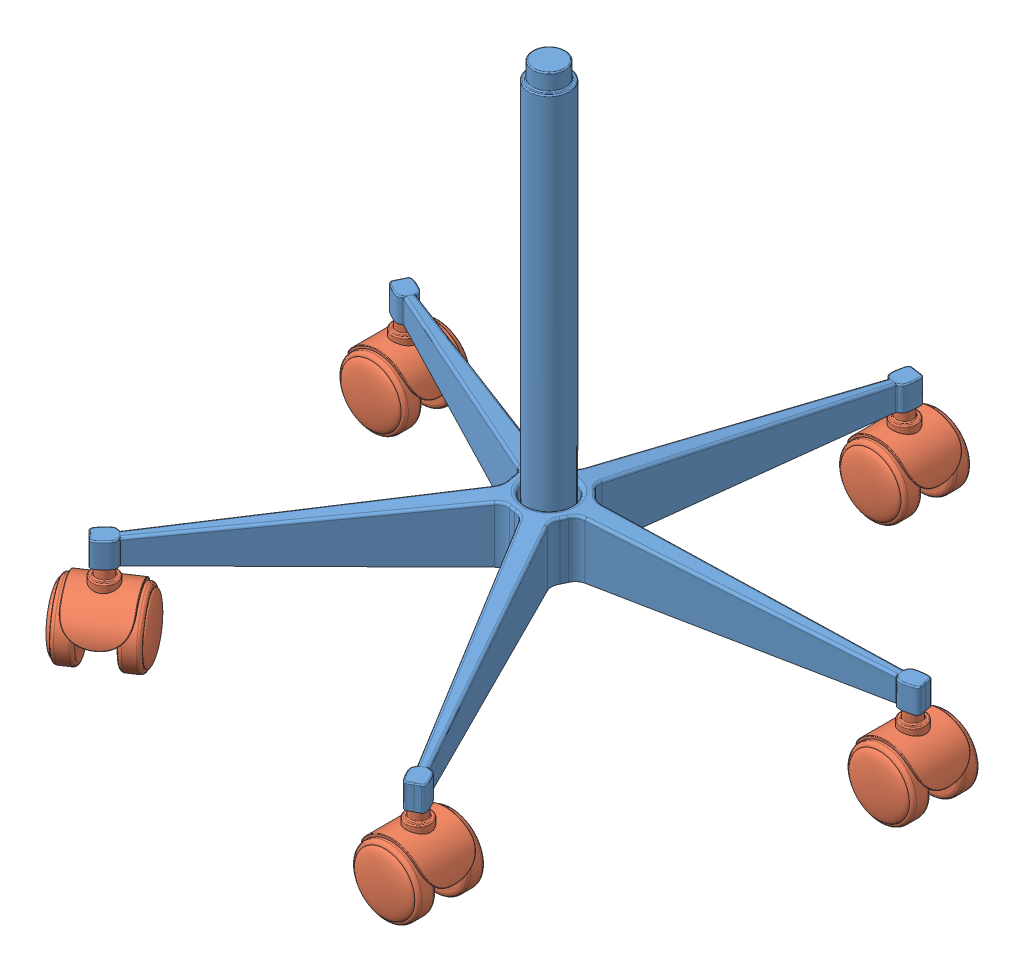
SolidWorks assembly bottom, configuration Default. Lengths in mm.
Overall size (546.09 424.33 547.79).
6 component instances, 2 part files, 10 mates.
Components (placement in the parent):
- 02-1: 02 [Default] at (-32.5019 -25.4626 34.4497) size (506.04 353.78 503.49)
- wheel_ch-1: wheel_ch [Default] at (-222.1443 -68.5108 226.5) x (0.554353 0 0.832281) z (-0.832281 0 0.554353) size (60.82 70.55 65)
- wheel_ch-2: wheel_ch [Default] at (-263.9502 -68.5108 -66.3111) size (60.82 70.55 65)
- wheel_ch-3: wheel_ch [Default] at (3.6941 -68.5108 -208.1701) size (60.82 70.55 65)
- wheel_ch-4: wheel_ch [Default] at (221.3166 -68.5108 2.5378) size (60.82 70.55 65)
- wheel_ch-5: wheel_ch [Default] at (88.1705 -68.5108 274.6215) size (60.82 70.55 65)
Mates (geometry in assembly coordinates):
- Concentric1: concentric aligned: circle of 02-1; circle of wheel_ch-1
- Coincident1: coincident anti-aligned: plane of 02-1 through (-468.0495 -25.4626 31.9528) normal (0 -1 0); plane of wheel_ch-1 through (-208.5803 -25.4626 224.3156) normal (0 1 0)
- Concentric2: concentric aligned: circle of 02-1; circle of wheel_ch-2
- Coincident2: coincident anti-aligned: plane of 02-1 through (-468.0495 -25.4626 31.9528) normal (0 -1 0); plane of wheel_ch-2 through (-258.2489 -25.4626 -78.8111) normal (0 1 0)
- Concentric3: concentric aligned: circle of 02-1; circle of wheel_ch-3
- Coincident3: coincident anti-aligned: plane of 02-1 through (-468.0495 -25.4626 31.9528) normal (0 -1 0); plane of wheel_ch-3 through (9.3953 -25.4626 -220.6701) normal (0 1 0)
- Concentric4: concentric aligned: circle of 02-1; circle of wheel_ch-4
- Coincident4: coincident anti-aligned: plane of 02-1 through (-468.0495 -25.4626 31.9528) normal (0 -1 0); plane of wheel_ch-4 through (227.0179 -25.4626 -9.9622) normal (0 1 0)
- Concentric5: concentric aligned: circle of 02-1; circle of wheel_ch-5
- Coincident5: coincident anti-aligned: plane of 02-1 through (-468.0495 -25.4626 31.9528) normal (0 -1 0); plane of wheel_ch-5 through (93.8718 -25.4626 262.1215) normal (0 1 0)
